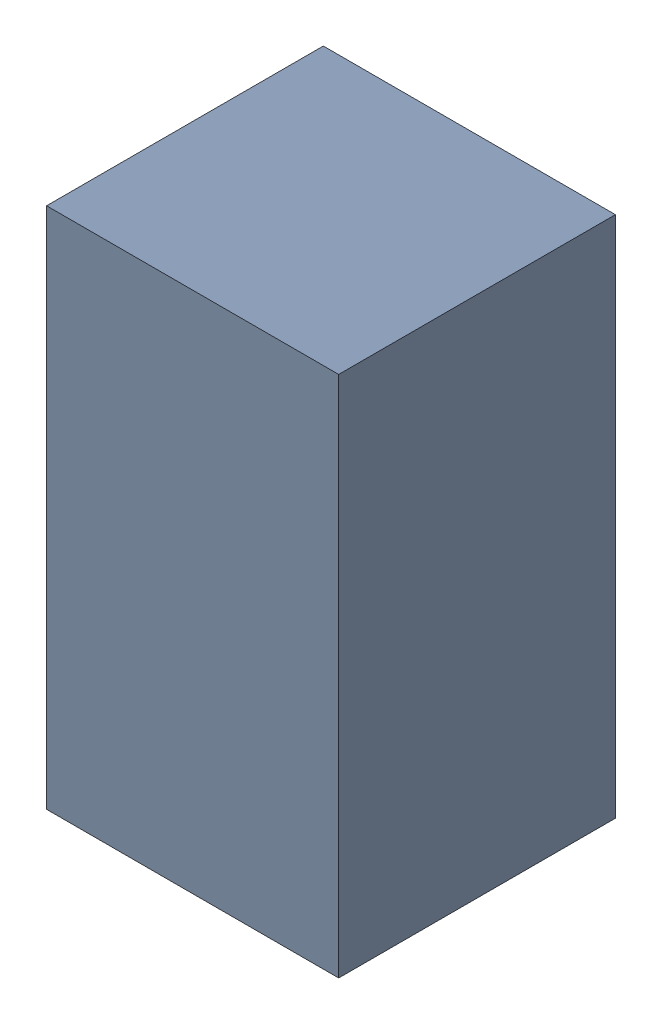
SolidWorks assembly R205, configuration Standard. Lengths in mm.
Overall size (0.95 1.7 0.9).
2 component instances, 1 part files, 0 mates.
Components (placement in the parent):
- 885541560-1: 885541560 [Standard] at (12.9 -14.2 0) size (0.95 1.7 0.9)
  - Extruded_16-1: Extruded_16 [Standard] at origin size (0.95 1.7 0.9)
